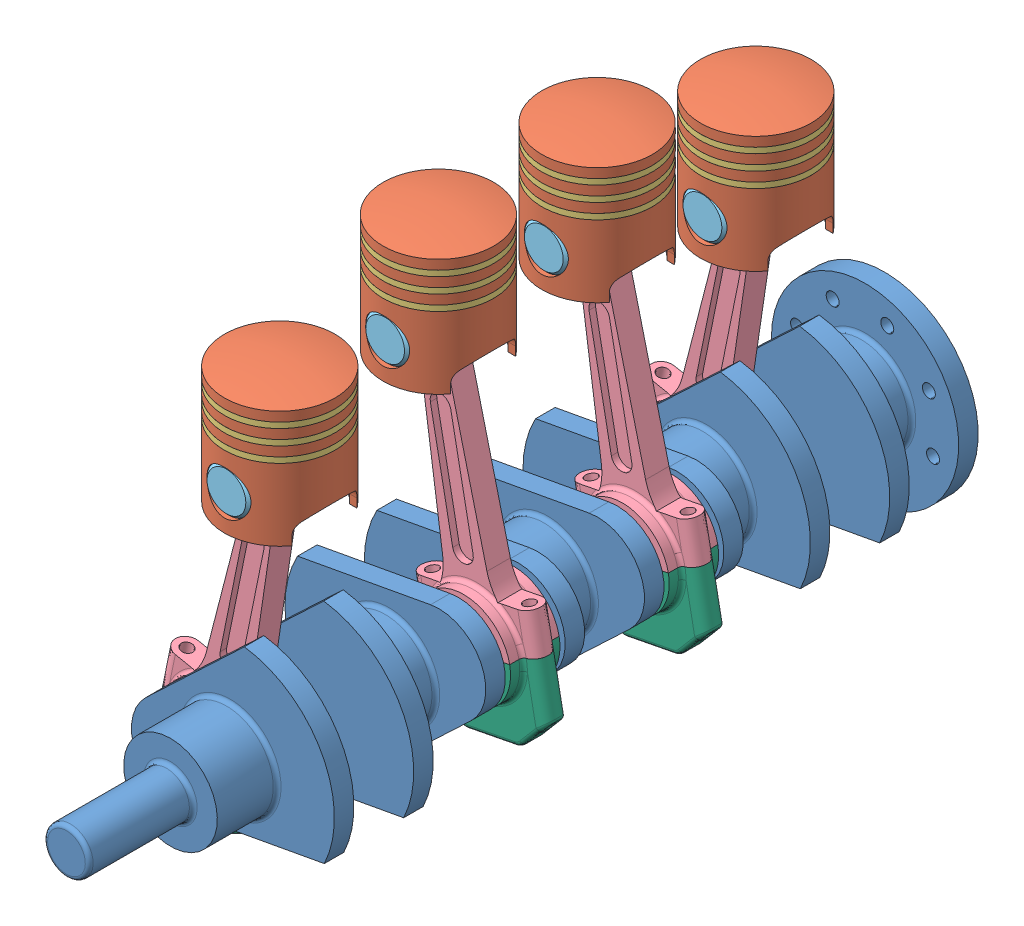
SolidWorks assembly final Assembly, configuration Default. Lengths in mm.
Overall size (207.83 387.38 629).
29 component instances, 6 part files, 75 mates.
Components (placement in the parent):
- 3.CRANKSHAFT-1: 3.CRANKSHAFT [Default] at (0 0 200) x (-0.452364 0.891833 0) z (0 0 1) size (144 160 629)
- 1.Piston-2: 1.Piston [Default] at (0 196.8523 421) size (85 95 85)
- 2Piston ring-2: 2Piston ring [Default] at (0 230.2523 421) x (0.984914 0 0.173043) z (-0.173043 0 0.984914) size (85 4.3 85)
- 4 connecting rod-1: 4 connecting rod [Default] at (0 178.8523 421) x (0.979996 -0.199019 0) z (0 0 1) size (94 223.7 38)
- 6. piston pin-2: 6. piston pin [Default] at (0 178.8523 421) size (33.8 33.8 82)
- 2Piston ring-3: 2Piston ring [Default] at (0 218.6523 421) size (85 4.3 85)
- 2Piston ring-4: 2Piston ring [Default] at (0 207.0523 421) size (85 4.3 85)
- 5.connecting rod cap-2: 5.connecting rod cap [Default] at (-40.0427 -18.3228 421) x (-0.979996 0.199019 0) z (0 0 1) size (94 60 38)
- 2Piston ring-5: 2Piston ring [Default] at (0 230.2523 55) size (85 4.3 85)
- 6. piston pin-3: 6. piston pin [Default] at (0 178.8523 55) size (33.8 33.8 82)
- 2Piston ring-6: 2Piston ring [Default] at (0 218.6523 55) size (85 4.3 85)
- 2Piston ring-7: 2Piston ring [Default] at (0 207.0523 55) size (85 4.3 85)
- 4 connecting rod-2: 4 connecting rod [Default] at (0 178.8523 55) x (0.979996 -0.199019 0) z (0 0 1) size (94 223.7 38)
- 5.connecting rod cap-5: 5.connecting rod cap [Default] at (-40.0427 -18.3228 55) x (-0.979996 0.199019 0) z (0 0 1) size (94 60 38)
- 1.Piston-3: 1.Piston [Default] at (0 196.8523 55) size (85 95 85)
- 2Piston ring-8: 2Piston ring [Default] at (0 270.3793 177) size (85 4.3 85)
- 6. piston pin-4: 6. piston pin [Default] at (0 218.9793 177) size (33.8 33.8 82)
- 2Piston ring-9: 2Piston ring [Default] at (0 258.7793 177) size (85 4.3 85)
- 2Piston ring-10: 2Piston ring [Default] at (0 247.1793 177) size (85 4.3 85)
- 4 connecting rod-3: 4 connecting rod [Default] at (0 218.9793 177) x (0.981581 0.191047 0) z (0 0 1) size (94 223.7 38)
- 5.connecting rod cap-6: 5.connecting rod cap [Default] at (38.4387 21.4852 177) x (-0.981581 -0.191047 0) z (0 0 1) size (94 60 38)
- 1.Piston-4: 1.Piston [Default] at (0 236.9793 177) size (85 95 85)
- 2Piston ring-11: 2Piston ring [Default] at (0 270.3793 299) size (85 4.3 85)
- 6. piston pin-5: 6. piston pin [Default] at (0 218.9793 299) size (33.8 33.8 82)
- 2Piston ring-12: 2Piston ring [Default] at (0 258.7793 299) size (85 4.3 85)
- 2Piston ring-13: 2Piston ring [Default] at (0 247.1793 299) size (85 4.3 85)
- 4 connecting rod-4: 4 connecting rod [Default] at (0 218.9793 299) x (0.981581 0.191047 0) z (0 0 1) size (94 223.7 38)
- 5.connecting rod cap-7: 5.connecting rod cap [Default] at (38.4387 21.4852 299) x (-0.981581 -0.191047 0) z (0 0 1) size (94 60 38)
- 1.Piston-5: 1.Piston [Default] at (0 236.9793 299) size (85 95 85)
Mates (geometry in assembly coordinates):
- Concentric1: concentric anti-aligned: cylinder of 3.CRANKSHAFT-1 through (0 0 585) axis (0 0 -1) radius 17.5
- Coincident3: coincident: plane of 3.CRANKSHAFT-1 through (0 0 585) normal (0 0 1)
- Coincident5: coincident aligned: plane of 1.Piston-2 through (0 196.8523 421) normal (0 0 1); plane of 6. piston pin-2 through (0 178.8523 421) normal (0 0 1)
- Coincident9: coincident aligned: plane of 1.Piston-2 through (0 196.8523 421) normal (0 0 1); plane of 6. piston pin-2 through (0 178.8523 421) normal (0 0 1)
- Concentric20: concentric anti-aligned: axis of 1.Piston-2 through (0 178.8523 440) axis (0 0 1); cylinder of 6. piston pin-2 through (0 178.8523 462) axis (0 0 -1) radius 16.9
- Coincident10: coincident anti-aligned: plane of 1.Piston-2 through (0 234.5523 463.5) normal (0 -1 0); plane of 2Piston ring-2 through (0 234.5523 421) normal (0 1 0)
- Concentric21: concentric aligned: cylinder of 1.Piston-2 through (0 196.8523 421) axis (0 -1 0) radius 39.5; cylinder of 2Piston ring-2 through (0 234.5523 421) axis (0 -1 0) radius 39.5
- Concentric22: concentric aligned: cylinder of 1.Piston-2 through (0 196.8523 421) axis (0 -1 0) radius 42.5; cylinder of 2Piston ring-3 through (0 222.9523 421) axis (0 -1 0) radius 39.5
- Coincident11: coincident anti-aligned: plane of 1.Piston-2 through (0 218.6523 463.5) normal (0 1 0); plane of 2Piston ring-3 through (0 218.6523 421) normal (0 -1 0)
- Coincident12: coincident anti-aligned: plane of 1.Piston-2 through (0 211.3523 463.5) normal (0 -1 0); plane of 2Piston ring-4 through (0 211.3523 421) normal (0 1 0)
- Concentric23: concentric aligned: cylinder of 1.Piston-2 through (0 196.8523 421) axis (0 -1 0) radius 39.5; cylinder of 2Piston ring-4 through (0 211.3523 421) axis (0 -1 0) radius 42.5
- Coincident13: coincident aligned: plane of 1.Piston-2 through (0 196.8523 421) normal (0 0 1); plane of 4 connecting rod-1 through (0 178.8523 421) normal (0 0 1)
- Coincident14: coincident aligned: plane of 1.Piston-2 through (0 196.8523 421) normal (0 0 1); plane of 4 connecting rod-1 through (0 178.8523 421) normal (0 0 1)
- Concentric25: concentric aligned: cylinder of 4 connecting rod-1 through (0 178.8523 440) axis (0 0 -1) radius 16.9; cylinder of 6. piston pin-2 through (0 178.8523 462) axis (0 0 -1) radius 16.9
- Coincident17: coincident anti-aligned: plane of 4 connecting rod-1 through (-40.0427 -18.3228 440) normal (-0.199019 -0.979996 0); plane of 5.connecting rod cap-2 through (-4.7628 -25.4875 440) normal (0.199019 0.979996 0)
- Concentric27: concentric aligned: cylinder of 4 connecting rod-1 through (-2.8029 -25.8856 421) axis (0.199019 0.979996 0) radius 4.5; cylinder of 5.connecting rod cap-2 through (-14.744 -84.6853 421) axis (0.199019 0.979996 0) radius 4.5
- Concentric28: concentric aligned: cylinder of 4 connecting rod-1 through (-77.2825 -10.7601 421) axis (0.199019 0.979996 0) radius 4.5; cylinder of 5.connecting rod cap-2 through (-89.2237 -69.5598 421) axis (0.199019 0.979996 0) radius 4.5
- Concentric29: concentric aligned: cylinder of 4 connecting rod-2 through (-2.8029 -25.8856 55) axis (0.199019 0.979996 0) radius 4.5; cylinder of 5.connecting rod cap-5 through (-14.744 -84.6853 55) axis (0.199019 0.979996 0) radius 4.5
- Concentric30: concentric aligned: cylinder of 2Piston ring-7 through (0 211.3523 55) axis (0 -1 0) radius 42.5; cylinder of 1.Piston-3 through (0 196.8523 55) axis (0 -1 0) radius 39.5
- Coincident18: coincident aligned: plane of 4 connecting rod-2 through (0 178.8523 55) normal (0 0 1); plane of 1.Piston-3 through (0 196.8523 55) normal (0 0 1)
- Concentric31: concentric anti-aligned: cylinder of 6. piston pin-3 through (0 178.8523 96) axis (0 0 -1) radius 16.9; line of 1.Piston-3 through (0 178.8523 74) axis (0 0 1)
- Concentric32: concentric aligned: cylinder of 2Piston ring-5 through (0 234.5523 55) axis (0 -1 0) radius 39.5; cylinder of 1.Piston-3 through (0 196.8523 55) axis (0 -1 0) radius 39.5
- Coincident19: coincident anti-aligned: plane of 4 connecting rod-2 through (-40.0427 -18.3228 74) normal (-0.199019 -0.979996 0); plane of 5.connecting rod cap-5 through (-4.7628 -25.4875 74) normal (0.199019 0.979996 0)
- Concentric33: concentric aligned: cylinder of 2Piston ring-6 through (0 222.9523 55) axis (0 -1 0) radius 39.5; cylinder of 1.Piston-3 through (0 196.8523 55) axis (0 -1 0) radius 42.5
- Coincident20: coincident aligned: plane of 4 connecting rod-2 through (0 178.8523 55) normal (0 0 1); plane of 1.Piston-3 through (0 196.8523 55) normal (0 0 1)
- Coincident21: coincident aligned: plane of 6. piston pin-3 through (0 178.8523 55) normal (0 0 1); plane of 1.Piston-3 through (0 196.8523 55) normal (0 0 1)
- Coincident22: coincident aligned: plane of 6. piston pin-3 through (0 178.8523 55) normal (0 0 1); plane of 1.Piston-3 through (0 196.8523 55) normal (0 0 1)
- Coincident23: coincident anti-aligned: plane of 2Piston ring-5 through (0 234.5523 55) normal (0 1 0); plane of 1.Piston-3 through (0 234.5523 97.5) normal (0 -1 0)
- Coincident24: coincident anti-aligned: plane of 2Piston ring-6 through (0 218.6523 55) normal (0 -1 0); plane of 1.Piston-3 through (0 218.6523 97.5) normal (0 1 0)
- Coincident25: coincident anti-aligned: plane of 2Piston ring-7 through (0 211.3523 55) normal (0 1 0); plane of 1.Piston-3 through (0 211.3523 97.5) normal (0 -1 0)
- Concentric34: concentric aligned: cylinder of 4 connecting rod-2 through (-77.2825 -10.7601 55) axis (0.199019 0.979996 0) radius 4.5; cylinder of 5.connecting rod cap-5 through (-89.2237 -69.5598 55) axis (0.199019 0.979996 0) radius 4.5
- Concentric35: concentric aligned: cylinder of 6. piston pin-3 through (0 178.8523 96) axis (0 0 -1) radius 16.9; cylinder of 4 connecting rod-2 through (0 178.8523 74) axis (0 0 -1) radius 16.9
- Concentric36: concentric aligned: cylinder of 4 connecting rod-3 through (75.7387 28.745 177) axis (-0.191047 0.981581 0) radius 4.5; cylinder of 5.connecting rod cap-6 through (87.2015 -30.1499 177) axis (-0.191047 0.981581 0) radius 4.5
- Concentric37: concentric aligned: cylinder of 2Piston ring-10 through (0 251.4793 177) axis (0 -1 0) radius 42.5; cylinder of 1.Piston-4 through (0 236.9793 177) axis (0 -1 0) radius 39.5
- Coincident26: coincident aligned: plane of 4 connecting rod-3 through (0 218.9793 177) normal (0 0 1); plane of 1.Piston-4 through (0 236.9793 177) normal (0 0 1)
- Concentric38: concentric anti-aligned: cylinder of 6. piston pin-4 through (0 218.9793 218) axis (0 0 -1) radius 16.9; line of 1.Piston-4 through (0 218.9793 196) axis (0 0 1)
- Concentric39: concentric aligned: cylinder of 2Piston ring-8 through (0 274.6793 177) axis (0 -1 0) radius 39.5; cylinder of 1.Piston-4 through (0 236.9793 177) axis (0 -1 0) radius 39.5
- Coincident27: coincident anti-aligned: plane of 4 connecting rod-3 through (38.4387 21.4852 196) normal (0.191047 -0.981581 0); plane of 5.connecting rod cap-6 through (73.7756 28.3629 196) normal (-0.191047 0.981581 0)
- Concentric40: concentric aligned: cylinder of 2Piston ring-9 through (0 263.0793 177) axis (0 -1 0) radius 39.5; cylinder of 1.Piston-4 through (0 236.9793 177) axis (0 -1 0) radius 42.5
- Coincident28: coincident aligned: plane of 4 connecting rod-3 through (0 218.9793 177) normal (0 0 1); plane of 1.Piston-4 through (0 236.9793 177) normal (0 0 1)
- Coincident29: coincident aligned: plane of 6. piston pin-4 through (0 218.9793 177) normal (0 0 1); plane of 1.Piston-4 through (0 236.9793 177) normal (0 0 1)
- Coincident30: coincident aligned: plane of 6. piston pin-4 through (0 218.9793 177) normal (0 0 1); plane of 1.Piston-4 through (0 236.9793 177) normal (0 0 1)
- Coincident31: coincident anti-aligned: plane of 2Piston ring-8 through (0 274.6793 177) normal (0 1 0); plane of 1.Piston-4 through (0 274.6793 219.5) normal (0 -1 0)
- Coincident32: coincident anti-aligned: plane of 2Piston ring-9 through (0 258.7793 177) normal (0 -1 0); plane of 1.Piston-4 through (0 258.7793 219.5) normal (0 1 0)
- Coincident33: coincident anti-aligned: plane of 2Piston ring-10 through (0 251.4793 177) normal (0 1 0); plane of 1.Piston-4 through (0 251.4793 219.5) normal (0 -1 0)
- Concentric41: concentric aligned: cylinder of 4 connecting rod-3 through (1.1386 14.2254 177) axis (-0.191047 0.981581 0) radius 4.5; cylinder of 5.connecting rod cap-6 through (12.6014 -44.6695 177) axis (-0.191047 0.981581 0) radius 4.5
- Concentric42: concentric aligned: cylinder of 6. piston pin-4 through (0 218.9793 218) axis (0 0 -1) radius 16.9; cylinder of 4 connecting rod-3 through (0 218.9793 196) axis (0 0 -1) radius 16.9
- Concentric43: concentric aligned: cylinder of 4 connecting rod-4 through (75.7387 28.745 299) axis (-0.191047 0.981581 0) radius 4.5; cylinder of 5.connecting rod cap-7 through (87.2015 -30.1499 299) axis (-0.191047 0.981581 0) radius 4.5
- Concentric44: concentric aligned: cylinder of 2Piston ring-13 through (0 251.4793 299) axis (0 -1 0) radius 42.5; cylinder of 1.Piston-5 through (0 236.9793 299) axis (0 -1 0) radius 39.5
- Coincident34: coincident aligned: plane of 4 connecting rod-4 through (0 218.9793 299) normal (0 0 1); plane of 1.Piston-5 through (0 236.9793 299) normal (0 0 1)
- Concentric45: concentric anti-aligned: cylinder of 6. piston pin-5 through (0 218.9793 340) axis (0 0 -1) radius 16.9; line of 1.Piston-5 through (0 218.9793 318) axis (0 0 1)
- Concentric46: concentric aligned: cylinder of 2Piston ring-11 through (0 274.6793 299) axis (0 -1 0) radius 39.5; cylinder of 1.Piston-5 through (0 236.9793 299) axis (0 -1 0) radius 39.5
- Coincident35: coincident anti-aligned: plane of 4 connecting rod-4 through (38.4387 21.4852 318) normal (0.191047 -0.981581 0); plane of 5.connecting rod cap-7 through (73.7756 28.3629 318) normal (-0.191047 0.981581 0)
- Concentric47: concentric aligned: cylinder of 2Piston ring-12 through (0 263.0793 299) axis (0 -1 0) radius 39.5; cylinder of 1.Piston-5 through (0 236.9793 299) axis (0 -1 0) radius 42.5
- Coincident36: coincident aligned: plane of 4 connecting rod-4 through (0 218.9793 299) normal (0 0 1); plane of 1.Piston-5 through (0 236.9793 299) normal (0 0 1)
- Coincident37: coincident aligned: plane of 6. piston pin-5 through (0 218.9793 299) normal (0 0 1); plane of 1.Piston-5 through (0 236.9793 299) normal (0 0 1)
- Coincident38: coincident aligned: plane of 6. piston pin-5 through (0 218.9793 299) normal (0 0 1); plane of 1.Piston-5 through (0 236.9793 299) normal (0 0 1)
- Coincident39: coincident anti-aligned: plane of 2Piston ring-11 through (0 274.6793 299) normal (0 1 0); plane of 1.Piston-5 through (0 274.6793 341.5) normal (0 -1 0)
- Coincident40: coincident anti-aligned: plane of 2Piston ring-12 through (0 258.7793 299) normal (0 -1 0); plane of 1.Piston-5 through (0 258.7793 341.5) normal (0 1 0)
- Coincident41: coincident anti-aligned: plane of 2Piston ring-13 through (0 251.4793 299) normal (0 1 0); plane of 1.Piston-5 through (0 251.4793 341.5) normal (0 -1 0)
- Concentric48: concentric aligned: cylinder of 4 connecting rod-4 through (1.1386 14.2254 299) axis (-0.191047 0.981581 0) radius 4.5; cylinder of 5.connecting rod cap-7 through (12.6014 -44.6695 299) axis (-0.191047 0.981581 0) radius 4.5
- Concentric49: concentric aligned: cylinder of 6. piston pin-5 through (0 218.9793 340) axis (0 0 -1) radius 16.9; cylinder of 4 connecting rod-4 through (0 218.9793 318) axis (0 0 -1) radius 16.9
- Concentric50: concentric aligned: cylinder of 5.connecting rod cap-2 through (-40.0427 -18.3228 440) axis (0 0 -1) radius 27; cylinder of 3.CRANKSHAFT-1 through (-40.0427 -18.3228 444) axis (0 0 -1) radius 27
- Width2: width anti-aligned: plane of 4 connecting rod-1 through (0 178.8523 430) normal (0 0 1); plane of 4 connecting rod-1 through (0 178.8523 412) normal (0 0 -1); plane of 3.CRANKSHAFT-1 through (0 0 444) normal (0 0 -1); plane of 3.CRANKSHAFT-1 through (0 0 398) normal (0 0 1)
- Concentric51: concentric aligned: cylinder of 3.CRANKSHAFT-1 through (38.4387 21.4852 322) axis (0 0 -1) radius 27; cylinder of 5.connecting rod cap-7 through (38.4387 21.4852 318) axis (0 0 -1) radius 27
- Width3: width aligned: plane of 4 connecting rod-4 through (0 218.9793 290) normal (0 0 -1); plane of 4 connecting rod-4 through (0 218.9793 308) normal (0 0 1); plane of 3.CRANKSHAFT-1 through (0 0 322) normal (0 0 -1); plane of 3.CRANKSHAFT-1 through (0 0 276) normal (0 0 1)
- Width4: width aligned: plane of 4 connecting rod-3 through (0 218.9793 186) normal (0 0 1); plane of 4 connecting rod-3 through (0 218.9793 168) normal (0 0 -1); plane of 3.CRANKSHAFT-1 through (0 0 154) normal (0 0 1); plane of 3.CRANKSHAFT-1 through (0 0 200) normal (0 0 -1)
- Concentric54: concentric anti-aligned: cylinder of 3.CRANKSHAFT-1 through (38.4387 21.4852 154) axis (0 0 1) radius 27; cylinder of 5.connecting rod cap-6 through (38.4387 21.4852 196) axis (0 0 -1) radius 27
- Width5: width anti-aligned: plane of 4 connecting rod-2 through (0 178.8523 46) normal (0 0 -1); plane of 4 connecting rod-2 through (0 178.8523 64) normal (0 0 1); plane of 3.CRANKSHAFT-1 through (0 0 32) normal (0 0 1); plane of 3.CRANKSHAFT-1 through (0 0 78) normal (0 0 -1)
- Concentric55: concentric anti-aligned: cylinder of 3.CRANKSHAFT-1 through (-40.0427 -18.3228 32) axis (0 0 1) radius 27; cylinder of 5.connecting rod cap-5 through (-40.0427 -18.3228 74) axis (0 0 -1) radius 27
- Parallel1: parallel anti-aligned: line of 1.Piston-2 through (0 266.2749 421) axis (0 -1 0)
- Coincident42: coincident anti-aligned: line of 1.Piston-3 through (0 268.4147 55) axis (0 -1 0)
- Coincident43: coincident anti-aligned: line of 1.Piston-4 through (0 308.5417 177) axis (0 -1 0)
- Coincident44: coincident anti-aligned: line of 1.Piston-5 through (0 308.5417 299) axis (0 -1 0)
- Coincident45: coincident anti-aligned: line of 1.Piston-2 through (0 268.4147 421) axis (0 -1 0)
